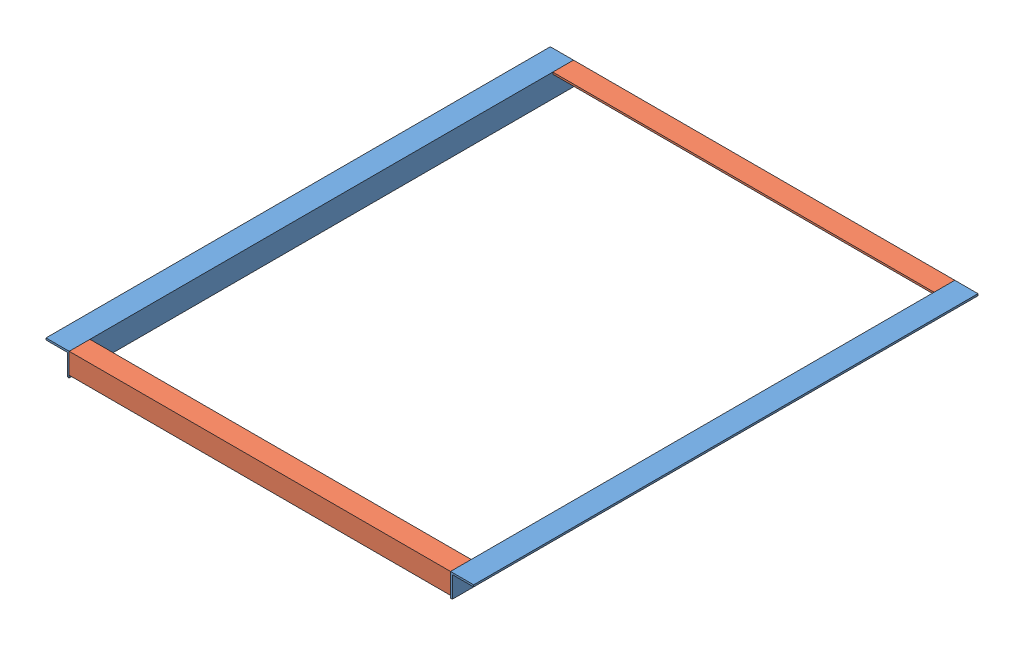
SolidWorks assembly ТумбаСБ, configuration По умолчанию. Lengths in mm.
Overall size (695.4 37.7 820).
4 component instances, 2 part files, 14 mates.
Components (placement in the parent):
- БокУ37-1: БокУ37 [По умолчанию] x (0 0 -1) z (0 1 0) size (820 37.7 37.7)
- ТылУ33-1: ТылУ33 [По умолчанию] at (620 0 -820) x (-1 0 0) z (0 1 0) size (620 33.7 33.7)
- БокУ37-2: БокУ37 [По умолчанию] at (620 0 0) x (0 0 -1) z (-1 0 0) size (820 37.7 37.7)
- ТылУ33-2: ТылУ33 [По умолчанию] x (1 0 0) z (0 1 0) size (620 33.7 33.7)
Mates (geometry in assembly coordinates):
- Совпадение1: coincident: plane of БокУ37-1 through (0 0 -820) normal (1 0 0); plane of assembly through (0 0 0) normal (1 0 0)
- Совпадение2: coincident: point of БокУ37-1; point of assembly
- Совпадение3: coincident aligned: plane of БокУ37-1 through (-37.7 0 -820) normal (0 1 0); plane of assembly through (0 0 0) normal (0 1 0)
- Совпадение4: coincident aligned: plane of БокУ37-1 through (-37.7 0 -820) normal (0 1 0); plane of БокУ37-2 through (620 0 -820) normal (0 1 0)
- Параллельность1: parallel anti-aligned: plane of БокУ37-1 through (0 0 -820) normal (1 0 0); plane of БокУ37-2 through (620 -37.7 -820) normal (-1 0 0)
- Совпадение6: coincident aligned: plane of ТылУ33-1 through (0 0 -786.3) normal (0 1 0); plane of БокУ37-2 through (620 0 -820) normal (0 1 0)
- Совпадение7: coincident anti-aligned: plane of БокУ37-1 through (0 0 -820) normal (1 0 0); plane of ТылУ33-1 through (0 0 -820) normal (-1 0 0)
- Совпадение8: coincident aligned: plane of ТылУ33-1 through (0 0 -786.3) normal (0 1 0); plane of ТылУ33-2 through (620 0 -52.132) normal (0 1 0)
- Параллельность2: parallel anti-aligned: plane of ТылУ33-1 through (0 0 -820) normal (0 0 -1); plane of ТылУ33-2 through (620 0 -18.432) normal (0 0 1)
- Совпадение10: coincident aligned: plane of БокУ37-1 through (0 0 -820) normal (0 0 -1); plane of ТылУ33-1 through (0 0 -820) normal (0 0 -1)
- Совпадение11: coincident anti-aligned: plane of ТылУ33-1 through (620 0 -820) normal (1 0 0); plane of БокУ37-2 through (620 -37.7 -820) normal (-1 0 0)
- Совпадение12: coincident aligned: plane of БокУ37-1 through (0 0 -820) normal (0 0 -1); plane of БокУ37-2 through (620 0 -820) normal (0 0 -1)
- Совпадение13: coincident anti-aligned: plane of БокУ37-2 through (620 -37.7 -820) normal (-1 0 0); plane of ТылУ33-2 through (620 0 -18.432) normal (1 0 0)
- Совпадение14: coincident aligned: plane of БокУ37-1 through (0 0 0) normal (0 0 1); plane of ТылУ33-2 through (620 0 0) normal (0 0 1)
